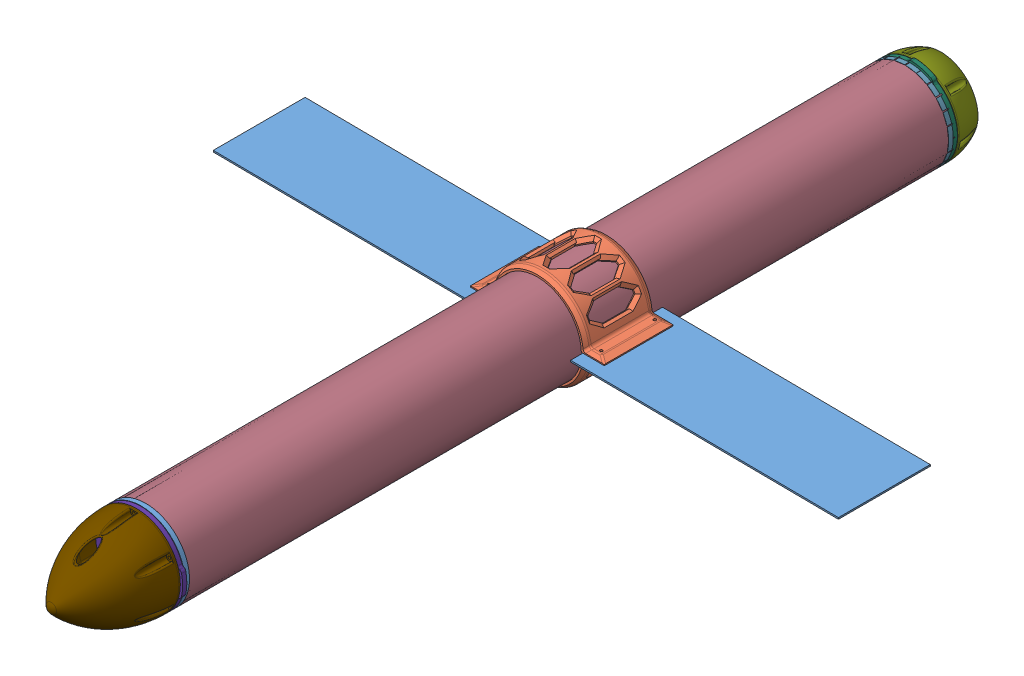
SolidWorks assembly Albatross_Assembly201903081857, configuration Default. Lengths in mm.
Overall size (816.95 156.14 1165.13).
119 component instances, 56 part files, 36 mates.
Components (placement in the parent):
- Front_WTE4-M-FLANGE-SEAL-R2-1: Front_WTE4-M-FLANGE-SEAL-R2 [默认] at (338.1764 686.4065 1049.3568) size (114.3 114.3 27.53)
- Main Ballast Tank-1: Main Ballast Tank [Default] at (332.7763 642.9544 942.3173) size (104.09 101.96 419.5)
  - Engine_endcap_mount-1: Engine_endcap_mount [默认] at (605.4001 -106.548 107.0395) x (-1 0 0) z (0 0 -1) size (100 100 15)
  - Engine_end_connector-1: Engine_end_connector [默认] at (-444.5999 -106.548 75.0395) size (100 100 25)
  - Syringe_clamp_front-2: Syringe_clamp_front [默认] at (155.4001 -106.548 75.0395) x (-1 0 0) z (0 0 -1) size (100 100 20)
  - Syringe_clamp_back-1: Syringe_clamp_back [默认] at (-144.5999 43.452 -49.0312) size (100 100 20)
  - Syringe_plunger_back-1: Syringe_plunger_back [默认] at (305.4001 43.452 -112.9677) x (-1 0 0) z (0 0 -1) size (100 98.49 25)
  - Buoyancy_engine_bearing_plate-1: Buoyancy_engine_bearing_plate [默认] at (155.3708 46.4151 -307.9605) x (0.999805 0.019754 0) z (0 0 1) size (100 100 25)
  - Buoyancy_engine_motor_mount-1: Buoyancy_engine_motor_mount [默认] at (308.3047 -100.5925 -209.9605) x (-0.999805 -0.019754 0) z (0 0 -1) size (100 100 20)
  - 8mm_acme_300mm-1: 8mm_acme_300mm [默认] at (-114.5999 43.452 109.0395) x (1 0 0) z (0 -1 0) size (9.24 302.5 8)
  - 8mm_smooth_rod_330mm-1: 8mm_smooth_rod_330mm [默认] at (-93.7998 2.9599 100.0395) x (1 0 0) z (0 -1 0) size (8 330 8)
  - Syringe_barrel-1: Syringe_barrel [默认] at (-27.5999 43.452 -44.0312) x (1 0 0) z (0 -1 0) size (31.2 149 31.2)
  - Syringe_plunger-1: Syringe_plunger [默认] at (-27.4985 43.188 -112.9677) x (0.913504 -0.40683 0) z (-0.40683 -0.913504 0) size (29 126.4 29)
  - Syringe_plunger_rubber-1: Syringe_plunger_rubber [默认] at (-27.2521 42.5347 4.7123) x (1 0 0) z (0 0 -1) size (29.91 29.91 12.8)
  - Syringe_plunger_rubber-2: Syringe_plunger_rubber [默认] at (-11.3881 71.0792 4.7123) x (0.5 -0.866025 0) z (0 0 -1) size (29.91 29.91 12.8)
  - Syringe_plunger_rubber-3: Syringe_plunger_rubber [默认] at (21.2641 71.6127 4.7123) x (-0.5 -0.866025 0) z (0 0 -1) size (29.91 29.91 12.8)
  - Syringe_plunger_rubber-4: Syringe_plunger_rubber [默认] at (38.0523 43.6019 4.7123) x (-1 0 0) z (0 0 -1) size (29.91 29.91 12.8)
  - Syringe_plunger_rubber-5: Syringe_plunger_rubber [默认] at (22.1883 15.0574 4.7123) x (-0.5 0.866025 0) z (0 0 -1) size (29.91 29.91 12.8)
  - Syringe_plunger_rubber-6: Syringe_plunger_rubber [默认] at (-10.4639 14.5239 4.7123) x (0.5 0.866025 0) z (0 0 -1) size (29.91 29.91 12.8)
  - Syringe_plunger-2: Syringe_plunger [默认] at (-10.9456 71.6192 -112.9677) x (0.104427 -0.994533 0) z (-0.994533 -0.104427 0) size (29 126.4 29)
  - Syringe_plunger-3: Syringe_plunger [默认] at (21.9531 71.4995 -112.9677) x (-0.809077 -0.587702 0) z (-0.587702 0.809077 0) size (29 126.4 29)
  - Syringe_plunger-4: Syringe_plunger [默认] at (38.2988 42.9486 -112.9677) x (-0.913504 0.40683 0) z (0.40683 0.913504 0) size (29 126.4 29)
  - Syringe_plunger-5: Syringe_plunger [默认] at (21.7458 14.5174 -112.9677) x (-0.104427 0.994533 0) z (0.994533 0.104427 0) size (29 126.4 29)
  - Syringe_plunger-6: Syringe_plunger [默认] at (-11.1528 14.637 -112.9677) x (0.809077 0.587702 0) z (0.587702 -0.809077 0) size (29 126.4 29)
  - Syringe_barrel-2: Syringe_barrel [默认] at (-10.7676 71.839 -44.0312) x (0.5 -0.866025 0) z (-0.866025 -0.5 0) size (31.2 149 31.2)
  - Syringe_barrel-3: Syringe_barrel [默认] at (22.2324 71.4553 -44.0312) x (-0.5 -0.866025 0) z (-0.866025 0.5 0) size (31.2 149 31.2)
  - Syringe_barrel-4: Syringe_barrel [默认] at (38.4001 42.6846 -44.0312) x (-1 0 0) z (0 1 0) size (31.2 149 31.2)
  - Syringe_barrel-5: Syringe_barrel [默认] at (21.5678 14.2976 -44.0312) x (-0.5 0.866025 0) z (0.866025 0.5 0) size (31.2 149 31.2)
  - Syringe_barrel-6: Syringe_barrel [默认] at (-11.4322 14.6813 -44.0312) x (0.5 0.866025 0) z (0.866025 -0.5 0) size (31.2 149 31.2)
  - LM8UU-1: LM8UU [默认] at (40.4741 123.702 -137.9677) x (0 1 0) z (1 0 0) size (15 24 15)
  - LM8UU-2: LM8UU [默认] at (-81.6354 33.702 -137.9677) x (-0.866025 -0.5 0) z (-0.5 0.866025 0) size (15 24 15)
  - LM8UU-3: LM8UU [默认] at (57.3616 -27.048 -137.9677) x (0.866025 -0.5 0) z (-0.5 -0.866025 0) size (15 24 15)
  - 4mm_threaded_rod_300mm-1: 4mm_threaded_rod_300mm [默认] at (5.4064 -111.548 85.0395) x (0 1 0) z (1 0 0) size (4 300 4)
  - 4mm_threaded_rod_300mm-2: 4mm_threaded_rod_300mm [默认] at (139.6309 120.9575 85.0395) x (-0.866025 -0.5 0) z (-0.5 0.866025 0) size (4 300 4)
  - 4mm_threaded_rod_300mm-3: 4mm_threaded_rod_300mm [默认] at (-128.837 120.9466 85.0395) x (0.866025 -0.5 0) z (-0.5 -0.866025 0) size (4 300 4)
  - motors_17_42_60mm-1: motors_17_42_60mm [默认] at (5.4001 43.452 -269.9605) size (42.3 42.3 84)
  - 8mm_smooth_rod_330mm-2: 8mm_smooth_rod_330mm [默认] at (90.0673 -22.2116 100.0395) x (-0.5 0.866025 0) z (0.866025 0.5 0) size (8 330 8)
  - 8mm_smooth_rod_330mm-3: 8mm_smooth_rod_330mm [默认] at (19.9329 149.6078 100.0395) x (-0.5 -0.866025 0) z (-0.866025 0.5 0) size (8 330 8)
  - Chassis_beam_buoyancy_engine-1: Chassis_beam_buoyancy_engine [默认] at (947.4909 -422.5422 -306.9605) x (-0.875733 0.482795 0) z (0.482795 0.875733 0) size (10 96 5)
  - Chassis_beam_buoyancy_engine-2: Chassis_beam_buoyancy_engine [默认] at (-936.6906 509.4462 -306.9605) x (0.875733 -0.482795 0) z (-0.482795 -0.875733 0) size (10 96 5)
  - Chassis_beam_buoyancy_engine-3: Chassis_beam_buoyancy_engine [默认] at (880.0083 626.3294 -306.9605) x (-0.855979 -0.51701 0) z (-0.51701 0.855979 0) size (10 96 5)
  - Chassis_beam_buoyancy_engine-4: Chassis_beam_buoyancy_engine [默认] at (-869.2081 -539.4254 -306.9605) x (0.855979 0.51701 0) z (0.51701 -0.855979 0) size (10 96 5)
  - Coupling_19_25_5_8mm-1: Coupling_19_25_5_8mm [默认] at (5.3296 43.2797 -198.9605) x (0.713357 0.700801 0) z (0.700801 -0.713357 0) size (20 25 19.06)
- Adjustment cabin-1: Adjustment cabin [默认] at (338.4472 690.1304 520.8568) size (100 100 340)
  - Pogo_header_front_mount-1: Pogo_header_front_mount [默认] at (299.7292 -3.7239 87.5) size (100 100 25)
  - F8-16M-1: F8-16M [默认] at (119.7292 -3.7239 108.5) x (1 0 0) z (0 -1 0) size (16 5 16)
  - M8_bolt_40mm-2: M8_bolt_40mm [默认] at (-30.2708 -3.7239 78.5) x (1 0 0) z (0 -1 0) size (13 44 13)
  - F8-16M-2: F8-16M [默认] at (119.7292 -3.7239 82.5) x (1 0 0) z (0 -1 0) size (16 5 16)
  - LM8UU-1: LM8UU [默认] at (25.9542 15.7761 88.5) x (1 0 0) z (0 -1 0) size (15 24 15)
  - LM8UU-2: LM8UU [默认] at (3.5042 -36.1854 88.5) x (-0.5 -0.866025 0) z (-0.866025 0.5 0) size (15 24 15)
  - LM8UU-3: LM8UU [默认] at (-30.2708 9.2376 88.5) x (-0.5 0.866025 0) z (0.866025 0.5 0) size (15 24 15)
  - Pogo_header_slider_mount-1: Pogo_header_slider_mount [默认] at (-300.2708 -153.7239 73.6245) x (-1 0 0) z (0 0 -1) size (98 93.03 21)
  - 8mm_smooth_rod_45mm-1: 8mm_smooth_rod_45mm [默认] at (-26.4958 15.7761 98.6245) x (1 0 0) z (0 -1 0) size (8 45 8)
  - 8mm_smooth_rod_45mm-2: 8mm_smooth_rod_45mm [默认] at (-4.0458 -36.1854 98.6245) x (-0.5 0.866025 0) z (0.866025 0.5 0) size (8 45 8)
  - 8mm_smooth_rod_45mm-3: 8mm_smooth_rod_45mm [默认] at (29.7292 9.2376 98.6245) x (-0.5 -0.866025 0) z (-0.866025 0.5 0) size (8 45 8)
  - Pogo_header_back_mount-2: Pogo_header_back_mount [默认] at (-449.7708 32.2761 73.6245) x (-1 0 0) z (0 0 -1) size (42 26 50)
  - Acme_bearing_back-2: Acme_bearing_back [默认] at (-450.2708 -153.7239 68.6245) x (-1 0 0) z (0 0 -1) size (36.44 35.5 10)
  - 608ZZ-1: 608ZZ [默认] at (-30.2708 -3.7239 55.6245) x (-1 0 0) z (0 1 0) size (22 7 22)
  - Acme_bearing_front-1: Acme_bearing_front [默认] at (-450.2708 -303.7239 55.6245) x (-1 0 0) z (0 0 -1) size (36.44 35.5 16)
  - Battery_mount_bearings-1: Battery_mount_bearings [默认] at (-0.2708 -3.7239 -6.0228) x (-1 0 0) z (0 0 -1) size (98 69.8 25)
  - Battery_mount_acme-1: Battery_mount_acme [默认] at (-0.2708 -153.7239 -97.0228) size (98 69.8 40)
  - Battery_rods_cover-1: Battery_rods_cover [默认] at (599.7292 -3.7239 -98.0228) size (98 58 1)
  - Battery_mount_connector-1: Battery_mount_connector [默认] at (150.2292 11.2761 98.4772) x (1 0 0) z (0 1 0) size (50 91 30)
  - LM8UU-4: LM8UU [默认] at (79.7292 6.2761 -31.0228) x (1 0 0) z (0 -1 0) size (15 24 15)
  - LM8UU-5: LM8UU [默认] at (39.7292 6.2761 -31.0228) x (1 0 0) z (0 -1 0) size (15 24 15)
  - 18650-1: 18650 [默认] at (-30.2708 -3.7239 -77.0228) x (1 0 0) z (0 -1 0) size (18 68 18)
  - 18650-7: 18650 [默认] at (-26.2516 11.2761 -77.0228) x (0.866025 -0.5 0) z (-0.5 -0.866025 0) size (18 68 18)
  - 18650-8: 18650 [默认] at (-15.2708 22.2569 -77.0228) x (0.5 -0.866025 0) z (-0.866025 -0.5 0) size (18 68 18)
  - 18650-9: 18650 [默认] at (-0.2708 26.2761 -77.0228) x (0 -1 0) z (-1 0 0) size (18 68 18)
  - 18650-10: 18650 [默认] at (14.7292 22.2569 -77.0228) x (-0.5 -0.866025 0) z (-0.866025 0.5 0) size (18 68 18)
  - 18650-11: 18650 [默认] at (25.7099 11.2761 -77.0228) x (-0.866025 -0.5 0) z (-0.5 0.866025 0) size (18 68 18)
  - 18650-12: 18650 [默认] at (29.7292 -3.7239 -77.0228) x (-1 0 0) z (0 1 0) size (18 68 18)
  - Pitch_motor_mount-1: Pitch_motor_mount [默认] at (149.7292 -303.7239 -157.5) size (98 97.69 35)
  - motors_17_42_34mm-1: motors_17_42_34mm [默认] at (-56.8394 52.8447 -186.5) x (0.707107 -0.707107 0) z (0 0 1) size (42.3 42.3 58)
  - 8mm_rod_90mm-1: 8mm_rod_90mm [默认] at (-96.2708 -9.2239 -6.0228) x (1 0 0) z (0 -1 0) size (8 90 8)
  - 8mm_rod_90mm-11: 8mm_rod_90mm [默认] at (-106.2708 -9.2239 -6.0228) x (1 0 0) z (0 -1 0) size (8 90 8)
  - 8mm_rod_90mm-12: 8mm_rod_90mm [默认] at (-100.2708 -17.7239 -6.0228) x (1 0 0) z (0 -1 0) size (8 90 8)
  - 8mm_rod_90mm-15: 8mm_rod_90mm [默认] at (-80.2708 -19.7239 -6.0228) x (1 0 0) z (0 -1 0) size (8 90 8)
  - 8mm_rod_90mm-16: 8mm_rod_90mm [默认] at (-96.7708 -26.7239 -6.0228) x (1 0 0) z (0 -1 0) size (8 90 8)
  - 8mm_rod_90mm-17: 8mm_rod_90mm [默认] at (-86.7708 -26.7239 -6.0228) x (1 0 0) z (0 -1 0) size (8 90 8)
  - 8mm_rod_90mm-18: 8mm_rod_90mm [默认] at (-90.2708 -17.7239 -6.0228) x (1 0 0) z (0 -1 0) size (8 90 8)
  - 8mm_rod_90mm-19: 8mm_rod_90mm [默认] at (95.7292 -9.2239 -6.0228) x (-1 0 0) z (0 1 0) size (8 90 8)
  - 8mm_rod_90mm-20: 8mm_rod_90mm [默认] at (99.7292 -17.7239 -6.0228) x (-1 0 0) z (0 1 0) size (8 90 8)
  - 8mm_rod_90mm-21: 8mm_rod_90mm [默认] at (96.2292 -26.7239 -6.0228) x (-1 0 0) z (0 1 0) size (8 90 8)
  - 8mm_rod_90mm-22: 8mm_rod_90mm [默认] at (86.2292 -26.7239 -6.0228) x (-1 0 0) z (0 1 0) size (8 90 8)
  - 8mm_rod_90mm-23: 8mm_rod_90mm [默认] at (79.7292 -19.7239 -6.0228) x (-1 0 0) z (0 1 0) size (8 90 8)
  - 8mm_rod_90mm-24: 8mm_rod_90mm [默认] at (105.7292 -9.2239 -6.0228) x (-1 0 0) z (0 1 0) size (8 90 8)
  - 8mm_rod_90mm-25: 8mm_rod_90mm [默认] at (89.7292 -17.7239 -6.0228) x (-1 0 0) z (0 1 0) size (8 90 8)
  - 8mm_smooth_rod_245mm-1: 8mm_smooth_rod_245mm [默认] at (-180.2708 6.2761 87.5) x (1 0 0) z (0 -1 0) size (8 245 8)
  - 8mm_smooth_rod_245mm-2: 8mm_smooth_rod_245mm [默认] at (-140.2708 6.2761 87.5) x (1 0 0) z (0 -1 0) size (8 245 8)
  - 8mm_acme_215mm-1: 8mm_acme_215mm [默认] at (-180.2708 -3.7239 81.5) x (1 0 0) z (0 -1 0) size (9.24 218.8 8)
  - Coupling_19_25_5_8mm-1: Coupling_19_25_5_8mm [默认] at (-0.2708 -3.7239 -141.5) x (1 0 0) z (0 -1 0) size (20 25 19.06)
  - 8mm_threaded_rod_105mm-1: 8mm_threaded_rod_105mm [默认] at (-140.2708 -33.7239 -6.0228) x (1 0 0) z (0 -1 0) size (8 105 8)
  - Pitch_motor_back_plate-1: Pitch_motor_back_plate [默认] at (299.7292 -303.7239 -217.5) size (98 83.69 20)
  - Chassis_beam_middle-1: Chassis_beam_middle [默认] at (41.4188 12.6232 -216.5) x (0.258819 -0.965926 0) z (0 0 1) size (10 5.25 83)
  - Chassis_beam_middle-2: Chassis_beam_middle [默认] at (4.7292 -48.2239 -216.5) x (-1 0 0) z (0 0 1) size (10 5.25 83)
  - Chassis_beam_middle-3: Chassis_beam_middle [默认] at (-44.5486 2.9639 -216.5) x (0.258819 0.965926 0) z (0 0 1) size (10 5.25 83)
- Control cabin-1: Control cabin [默认] at (239.0054 696.2498 279.339) x (1 0 0) z (0 -0.008727 0.999962) size (100 99.87 204.47)
  - parts_rough-2: parts_rough [默认] at (99.171 -9.6682 20.1029) x (-1 0 0) z (0 0.999962 -0.008727) size (100 30 87.5)
  - Roll_motor_mount-1: Roll_motor_mount [默认] at (999.171 -309.9186 -7.278) x (-1 0 0) z (0 -0.008727 -0.999962) size (100 84.7 20)
  - motors_17_42_34mm-1: motors_17_42_34mm [默认] at (19.171 -10.2267 -43.8947) x (1 0 0) z (0 0.008727 0.999962) size (42.3 42.3 58)
  - Circuit_rack_end-1: Circuit_rack_end [默认] at (849.171 -310.7243 -99.5995) x (-1 0 0) z (0 -0.008727 -0.999962) size (100 70.66 20)
  - Circuit_rack_endcap_mount-1: Circuit_rack_endcap_mount [默认] at (-350.829 -311.4021 -177.2715) x (1 0 0) z (0 0.008727 0.999962) size (100 99.7 20)
  - Control_board-1: Control_board [默认] at (141.716 -33.1654 -105.5219) x (-1 0 0) z (0 -0.999962 0.008727) size (85.09 66.67 20.6)
  - Fathom-S_mounting_bracket-1: Fathom-S_mounting_bracket [默认] at (849.171 -22.2567 -138.9558) x (-1 0 0) z (0 -0.999962 0.008727) size (97.61 66.67 11)
  - Chassis_beam_PCB_mount-1: Chassis_beam_PCB_mount [默认] at (-137.7847 1054.984 -19.6894) x (0.258819 -0.965889 0.008429) z (0.965926 0.258809 -0.002259) size (10 169 5)
  - Chassis_beam_PCB_mount-2: Chassis_beam_PCB_mount [默认] at (1189.171 -56.6826 -9.988) x (-1 0 0) z (0 -0.999962 0.008727) size (10 169 5)
  - Chassis_beam_PCB_mount-3: Chassis_beam_PCB_mount [默认] at (-228.0988 -1050.6541 -1.3137) x (0.258819 0.965889 -0.008429) z (-0.965926 0.258809 -0.002259) size (10 169 5)
  - F4-9M-1: F4-9M [默认] at (189.171 -9.6333 24.1027) x (1 0 0) z (0 0.999962 -0.008727) size (9 4 9)
- Round tube-3: Round tube [默认] at (338.1764 686.4065 545.3568) size (114.3 114.3 1000)
- Back_WTE4-M-FLANGE-SEAL-R2-1: Back_WTE4-M-FLANGE-SEAL-R2 [默认] at (338.1764 686.4065 99.3568) x (-1 0 0) z (0 0 -1) size (114.3 114.3 27.53)
- Rear_end_cap-1: Rear_end_cap [默认] at (338.1764 686.4065 66.3568) x (0.866025 0.5 0) z (0 0 1) size (114.3 114.3 6)
- Tail_endcap_shroud-2: Tail_endcap_shroud [默认] at (1023.7979 347.4033 66.3568) x (-0.965926 0.258819 0) z (0 0 -1) size (117.59 114.3 35)
- Front_end_cap-1: Front_end_cap [默认] at (338.1764 686.4065 1076.3568) size (120.3 114.3 6)
- Nosecone-1: Nosecone [默认] at (-261.8236 686.4065 1082.3568) size (114.3 120.64 114.13)
- Wings-1: Wings [默认] at (104.7092 688.9439 513.6971) x (0 0 -1) z (-0.008727 -0.999962 0) size (120 350 2)
- Wing_mount-1: Wing_mount [默认] at (935.5356 381.182 468.6971) x (0.999962 -0.008727 0) z (0 0 1) size (174.96 62 90)
- Wing_mount-2: Wing_mount [默认] at (-259.1828 991.631 468.6971) x (-0.999962 0.008727 0) z (0 0 1) size (174.96 62 90)
- Wings-2: Wings [默认] at (571.6348 682.8691 513.6971) x (0 0 -1) z (0.008727 0.999962 0) size (120 350 2)
Mates (geometry in assembly coordinates):
- 同心2: concentric anti-aligned: cylinder of ? through (338.1764 686.4065 1083.3568) axis (0 0 -1) radius 50.8; cylinder of Front_WTE4-M-FLANGE-SEAL-R2-1 through (338.1764 686.4065 1089.3568) axis (0 0 1) radius 44.419
- 重合1: coincident anti-aligned: plane of ? through (395.3264 686.4065 1083.3568) normal (0 0 1); plane of Front_WTE4-M-FLANGE-SEAL-R2-1 through (388.5954 686.4065 1083.3568) normal (0 0 -1)
- 同心3: concentric anti-aligned: cylinder of ? through (338.1764 686.4065 1083.3568) axis (0 0 -1) radius 57.15; cylinder of Main Ballast Tank-1/Engine_endcap_mount-1 through (338.1764 686.4065 1055.3568) axis (0 0 1) radius 50
- 重合2: coincident anti-aligned: plane of Front_WTE4-M-FLANGE-SEAL-R2-1 through (338.1764 686.4065 1049.3568) normal (0 0 -1); plane of Main Ballast Tank-1/Engine_endcap_mount-1 through (338.1764 686.4065 1049.3568) normal (0 0 1)
- 重合3: coincident anti-aligned: cylinder of Main Ballast Tank-1/Buoyancy_engine_bearing_plate-1 through (338.1764 686.4065 634.3568) axis (0 0 1) radius 50; circle of Adjustment cabin-1/Pogo_header_front_mount-1
- 重合4: coincident anti-aligned: plane of Main Ballast Tank-1/Buoyancy_engine_bearing_plate-1 through (338.1764 686.4065 634.3568) normal (0 0 -1); plane of Adjustment cabin-1/F8-16M-1 through (346.1764 686.4065 634.3568) normal (0 0 1)
- 同心4: concentric aligned: cylinder of Adjustment cabin-1/Pitch_motor_back_plate-1 through (338.1764 686.4065 308.3568) axis (0 0 -1) radius 49; cylinder of Control cabin-1/parts_rough-2 through (338.1764 686.4065 299.3568) axis (0 0 -1) radius 50
- 同心5: concentric anti-aligned: cylinder of Adjustment cabin-1/Pitch_motor_back_plate-1 through (338.1764 686.4065 308.3568) axis (0 0 -1) radius 4.1; cylinder of Control cabin-1/parts_rough-2 through (338.1764 686.4065 299.3568) axis (0 0 1) radius 2.5
- 同心6: concentric aligned: cylinder of Front_WTE4-M-FLANGE-SEAL-R2-1 through (338.1764 686.4065 1076.8835) axis (0 0 -1) radius 50.419; cylinder of Round tube-3 through (338.1764 686.4065 1020.3568) axis (0 0 -1) radius 57.15
- 重合5: coincident anti-aligned: plane of Front_WTE4-M-FLANGE-SEAL-R2-1 through (388.5954 686.4065 1070.3568) normal (0 0 -1); plane of Round tube-3 through (395.3264 686.4065 1070.3568) normal (0 0 1)
- 重合6: coincident anti-aligned: plane of Adjustment cabin-1/Pitch_motor_back_plate-1 through (918.6783 666.4065 303.3568) normal (0 0 -1); plane of Control cabin-1/F4-9M-1 through (340.1764 686.4065 303.3568) normal (0 0 1)
- 同心7: concentric anti-aligned: cylinder of Control cabin-1/Circuit_rack_endcap_mount-1 through (338.1764 686.4065 107.7155) axis (0 0 -1) radius 50; cylinder of Back_WTE4-M-FLANGE-SEAL-R2-1 through (338.1764 686.4065 71.8301) axis (0 0 1) radius 57.15
- 平行1: parallel anti-aligned: cylinder of Control cabin-1/Circuit_rack_endcap_mount-1 through (371.4104 719.6405 99.3568) axis (0 0 -1) radius 1.8; cylinder of Back_WTE4-M-FLANGE-SEAL-R2-1 through (371.4033 719.6334 99.3568) axis (0 0 1) radius 1.3
- 重合7: coincident anti-aligned: plane of Control cabin-1/Circuit_rack_endcap_mount-1 through (338.1764 636.4065 99.3568) normal (0 0 -1); plane of Back_WTE4-M-FLANGE-SEAL-R2-1 through (338.1764 686.4065 99.3568) normal (0 0 1)
- 同心11: concentric anti-aligned: cylinder of Back_WTE4-M-FLANGE-SEAL-R2-1 through (338.1764 686.4065 71.8301) axis (0 0 1) radius 57.15; cylinder of Rear_end_cap-1 through (338.1764 686.4065 72.3568) axis (0 0 -1) radius 57.15
- 同心12: concentric anti-aligned: cylinder of Back_WTE4-M-FLANGE-SEAL-R2-1 through (324.2066 738.5423 78.3568) axis (0 0 1) radius 1.3; cylinder of Rear_end_cap-1 through (324.2066 738.5423 66.3568) axis (0 0 -1) radius 1.6
- 同心13: concentric anti-aligned: cylinder of Back_WTE4-M-FLANGE-SEAL-R2-1 through (376.3425 724.5726 78.3568) axis (0 0 1) radius 1.3; cylinder of Rear_end_cap-1 through (376.3425 724.5726 66.3568) axis (0 0 -1) radius 1.6
- 重合8: coincident anti-aligned: plane of Back_WTE4-M-FLANGE-SEAL-R2-1 through (281.0264 686.4065 72.3568) normal (0 0 -1); plane of Rear_end_cap-1 through (338.1764 686.4065 72.3568) normal (0 0 1)
- 重合9: coincident anti-aligned: cylinder of Rear_end_cap-1 through (338.1764 686.4065 72.3568) axis (0 0 -1) radius 57.15; circle of Tail_endcap_shroud-2
- 同心14: concentric aligned: cylinder of Rear_end_cap-1 through (376.3425 724.5726 66.3568) axis (0 0 -1) radius 1.6; cylinder of Tail_endcap_shroud-2 through (376.3425 724.5726 34.1262) axis (0 0 -1) radius 1.8
- 重合10: coincident anti-aligned: plane of Rear_end_cap-1 through (338.1764 686.4065 66.3568) normal (0 0 -1); plane of Tail_endcap_shroud-2 through (338.1764 686.4065 66.3568) normal (0 0 1)
- 同心15: concentric anti-aligned: cylinder of Front_WTE4-M-FLANGE-SEAL-R2-1 through (338.1764 686.4065 1076.8835) axis (0 0 -1) radius 57.15; cylinder of Front_end_cap-1 through (338.1764 686.4065 1076.3568) axis (0 0 1) radius 57.15
- 同心16: concentric aligned: cylinder of Front_WTE4-M-FLANGE-SEAL-R2-1 through (384.9201 713.394 1070.3568) axis (0 0 -1) radius 1.3; cylinder of Front_end_cap-1 through (384.9201 713.394 1076.3568) axis (0 0 -1) radius 1.6
- 同心17: concentric aligned: cylinder of Front_WTE4-M-FLANGE-SEAL-R2-1 through (291.4327 659.419 1070.3568) axis (0 0 -1) radius 1.3; cylinder of Front_end_cap-1 through (291.4327 659.419 1076.3568) axis (0 0 -1) radius 1.6
- 重合11: coincident anti-aligned: plane of Front_WTE4-M-FLANGE-SEAL-R2-1 through (395.3264 686.4065 1076.3568) normal (0 0 1); plane of Front_end_cap-1 through (338.1764 686.4065 1076.3568) normal (0 0 -1)
- 同心18: concentric anti-aligned: cylinder of Front_end_cap-1 through (338.1764 686.4065 1076.3568) axis (0 0 1) radius 57.15; cylinder of Nosecone-1 through (338.1764 686.4065 1141.0973) axis (0 0 -1) radius 57.15
- 同心19: concentric aligned: cylinder of Front_end_cap-1 through (338.1764 740.3815 1076.3568) axis (0 0 -1) radius 1.6; cylinder of Nosecone-1 through (338.1764 740.3815 1082.3568) axis (0 0 -1) radius 1.8
- 重合12: coincident anti-aligned: plane of Front_end_cap-1 through (338.1764 686.4065 1082.3568) normal (0 0 1); plane of Nosecone-1 through (338.1764 632.8315 1082.3568) normal (0 0 -1)
- 同心20: concentric anti-aligned: cylinder of Round tube-3 through (338.1764 686.4065 1020.3568) axis (0 0 -1) radius 57.15; cylinder of Wing_mount-1 through (338.1764 686.4065 558.6971) axis (0 0 1) radius 57.5
- 同心21: concentric anti-aligned: cylinder of Round tube-3 through (338.1764 686.4065 1020.3568) axis (0 0 -1) radius 57.15; cylinder of Wing_mount-2 through (338.1764 686.4065 558.6971) axis (0 0 1) radius 57.5
- 同心23: concentric aligned: circle of Wings-1; cylinder of Wing_mount-2 through (264.642 680.5479 478.6971) axis (-0.008727 -0.999962 0) radius 1.7
- 同心24: concentric aligned: cylinder of Wings-1 through (264.7031 687.5477 548.6971) axis (-0.008727 -0.999962 0) radius 1.5; cylinder of Wing_mount-2 through (264.642 680.5479 548.6971) axis (-0.008727 -0.999962 0) radius 1.7
- 重合13: coincident anti-aligned: plane of Wings-1 through (104.6918 686.944 513.6971) normal (-0.008727 -0.999962 0); plane of Wing_mount-2 through (410.641 684.274 513.6971) normal (0.008727 0.999962 0)
- 同心25: concentric anti-aligned: cylinder of Wing_mount-2 through (411.5973 679.2655 548.6971) axis (-0.008727 -0.999962 0) radius 1.7; cylinder of Wings-2 through (411.6409 684.2653 548.6971) axis (0.008727 0.999962 0) radius 1.5
- 重合14: coincident anti-aligned: plane of Wing_mount-2 through (410.641 684.274 513.6971) normal (0.008727 0.999962 0); plane of Wings-2 through (571.6348 682.8691 513.6971) normal (-0.008727 -0.999962 0)
- 同心26: concentric anti-aligned: cylinder of Wings-1 through (264.7031 687.5477 548.6971) axis (-0.008727 -0.999962 0) radius 1.5; cylinder of Wing_mount-1 through (264.7555 693.5475 548.6971) axis (0.008727 0.999962 0) radius 1.7
